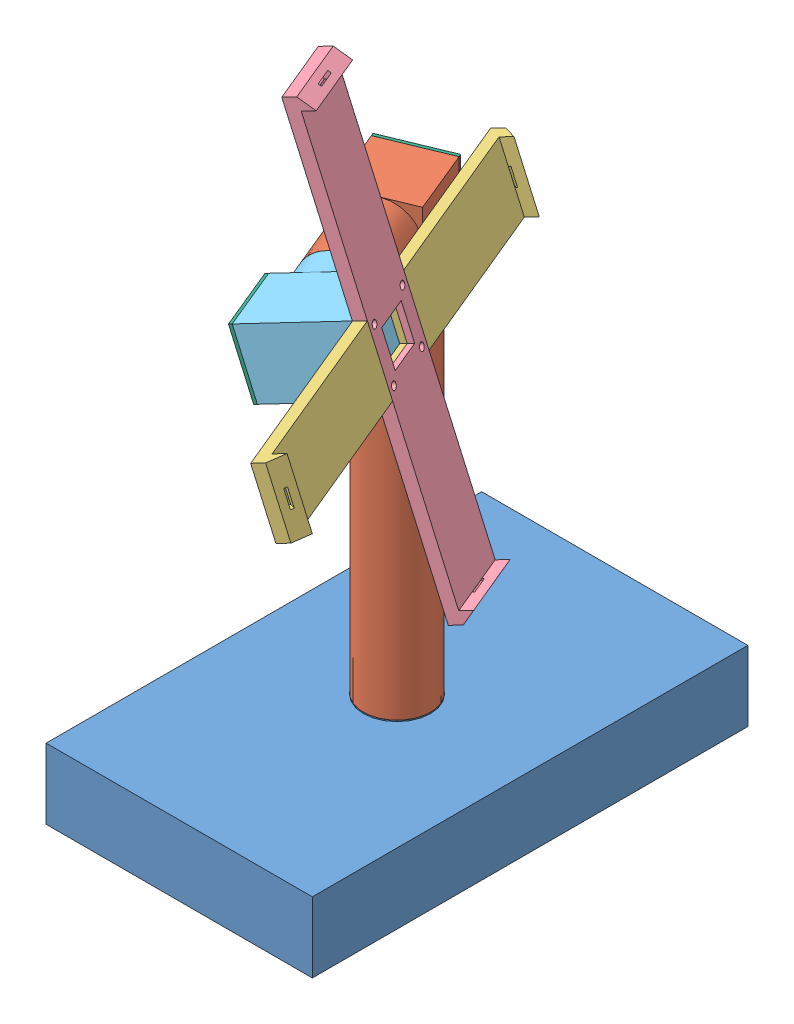
SolidWorks assembly Assem1, configuration Default. Lengths in mm.
Overall size (307.31 607.37 467.96).
7 component instances, 6 part files, 19 mates.
Components (placement in the parent):
- part1_model1b-1: part1_model1b [Default] at (134.7553 183.7096 304.2404) size (222.68 59.8 364.28)
- part2_modela-1: part2_modela [Default] at (145.4634 534.3096 330.2201) x (0.924546 0 -0.381071) z (0.381071 0 0.924546) size (56.2 377.7 117.5)
- part3_model1c-1: part3_model1c [Default] at (234.936 549.2363 415.9242) x (-0.381896 0.002984 -0.924201) z (0.885661 0.286961 -0.365044) size (370 56.2 20)
- part3_model1d-1: part3_model1d [Default] at (234.936 549.2363 415.9242) x (0.26412 -0.957938 -0.112232) z (0.885661 0.286961 -0.365044) size (370 56.2 20)
- part3_model2a-1: part3_model2a [Default] at (168.8231 534.3096 386.8948) x (0.885661 0.286961 -0.365044) z (0.381071 0 0.924546) size (80.34 56.2 80.2)
- tampa (2)-1: tampa (2) [Default] at (123.0945 534.3096 275.9493) x (0.924546 0 -0.381071) z (0.381071 0 0.924546) size (56.2 56.2 5)
- tampa (2)-2: tampa (2) [Default] at (161.5756 525.5286 446.234) x (-0.381071 0 -0.924546) z (0.885661 0.286961 -0.365044) size (56.2 56.2 5)
Mates (geometry in assembly coordinates):
- Coincident1: coincident: plane of assembly; plane of assembly; plane of part1_model1b-1 through (134.7553 184.7096 304.2404) normal (0 1 0); plane of part2_modela-1 through (134.7553 184.7096 304.2404) normal (0 -1 0)
- Concentric1: concentric: cylinder of assembly; cylinder of assembly; cylinder of part1_model1b-1 through (134.7553 184.7096 304.2404) axis (0 -1 0) radius 28.1; cylinder of part2_modela-1 through (134.7553 184.7096 304.2404) axis (0 1 0) radius 28.1
- Coincident2: coincident: plane of assembly; plane of assembly; plane of part2_modela-1 through (168.8231 534.3096 386.8948) normal (0.381071 0 0.924546); plane of part3_model2a-1 through (168.8231 534.3096 386.8948) normal (-0.381071 0 -0.924546)
- Concentric2: concentric: cylinder of assembly; cylinder of assembly; cylinder of part2_modela-1 through (168.8231 534.3096 386.8948) axis (-0.381071 0 -0.924546) radius 28.1; cylinder of part3_model2a-1 through (177.9688 534.3096 409.0839) axis (-0.381071 0 -0.924546) radius 28.1
- Coincident3: coincident: plane of assembly; plane of assembly; plane of part3_model1c-1 through (234.936 549.2363 415.9242) normal (-0.885661 -0.286961 0.365044); plane of part3_model2a-1 through (215.09 549.3005 367.8249) normal (0.885661 0.286961 -0.365044)
- Concentric3: concentric: cylinder of assembly; cylinder of assembly; cylinder of part3_model1c-1 through (221.0143 569.9441 398.4263) axis (0.885661 0.286961 -0.365044) radius 3; cylinder of part3_model2a-1 through (203.3011 564.2049 405.7272) axis (0.885661 0.286961 -0.365044) radius 3
- Coincident10: coincident: plane of assembly; plane of assembly; plane of part3_model1c-1 through (239.3643 550.6711 414.099) normal (0.885661 0.286961 -0.365044); plane of part3_model1d-1 through (239.3643 550.6711 414.099) normal (-0.885661 -0.286961 0.365044)
- Coincident11: coincident: plane of assembly; plane of assembly; plane of part3_model1c-1 through (236.0548 523.8369 384.9752) normal (0.381896 -0.002984 0.924201); plane of part3_model1d-1 through (186.8404 719.8288 405.9444) normal (-0.381896 0.002984 -0.924201)
- Coincident12: coincident: plane of assembly; plane of assembly; plane of part3_model1c-1 through (318.0461 524.6655 570.8551) normal (0.26412 -0.957938 -0.112232); plane of part3_model1d-1 through (257.5173 523.6692 436.9153) normal (-0.26412 0.957938 0.112232)
- Coincident13: coincident: plane of assembly; plane of assembly; plane of part2_modela-1 through (124.0472 534.3096 278.2607) normal (-0.381071 0 -0.924546); plane of tampa (2)-1 through (124.0472 534.3096 278.2607) normal (0.381071 0 0.924546)
- Coincident14: coincident: plane of assembly; plane of assembly; plane of part2_modela-1 through (150.0269 562.4096 267.5526) normal (0 1 0); plane of tampa (2)-1 through (98.0675 562.4096 288.9688) normal (0 1 0)
- Coincident15: coincident: plane of assembly; plane of assembly; plane of part2_modela-1 through (98.0675 506.2096 288.9688) normal (-0.924546 0 0.381071); plane of tampa (2)-1 through (98.0675 506.2096 288.9688) normal (-0.924546 0 0.381071)
- Coincident16: coincident: plane of assembly; plane of assembly; plane of part3_model2a-1 through (181.953 499.3279 468.2283) normal (-0.885661 -0.286961 0.365044); plane of tampa (2)-2 through (163.7898 526.246 445.3214) normal (0.885661 0.286961 -0.365044)
- Coincident17: coincident: plane of assembly; plane of assembly; plane of part3_model2a-1 through (167.0427 553.1642 474.3739) normal (-0.265308 0.957942 0.109352); plane of tampa (2)-2 through (167.0427 553.1642 474.3739) normal (-0.265308 0.957942 0.109352)
- Coincident18: coincident: plane of assembly; plane of assembly; plane of part3_model2a-1 through (199.385 534.3096 461.0434) normal (0.381071 0 0.924546); plane of tampa (2)-2 through (181.953 499.3279 468.2283) normal (0.381071 0 0.924546)
- Concentric4: concentric: cylinder of assembly; cylinder of assembly; cylinder of part3_model1c-1 through (248.8576 528.5284 433.4221) axis (0.885661 0.286961 -0.365044) radius 3; cylinder of part3_model1d-1 through (248.8576 528.5284 433.4221) axis (0.885661 0.286961 -0.365044) radius 3
- Concentric5: concentric: cylinder of assembly; cylinder of assembly; cylinder of part3_model1c-1 through (248.8576 528.5284 433.4221) axis (0.885661 0.286961 -0.365044) radius 3; cylinder of part3_model1d-1 through (248.8576 528.5284 433.4221) axis (0.885661 0.286961 -0.365044) radius 3
- Concentric6: concentric: cylinder of assembly; cylinder of assembly; cylinder of part3_model1c-1 through (232.3979 528.657 393.5891) axis (0.885661 0.286961 -0.365044) radius 3; cylinder of part3_model1d-1 through (232.3979 528.657 393.5891) axis (0.885661 0.286961 -0.365044) radius 3
- Concentric7: concentric: cylinder of assembly; cylinder of assembly; cylinder of part3_model1c-1 through (237.4741 569.8155 438.2593) axis (0.885661 0.286961 -0.365044) radius 3; cylinder of part3_model1d-1 through (237.4741 569.8155 438.2593) axis (0.885661 0.286961 -0.365044) radius 3
